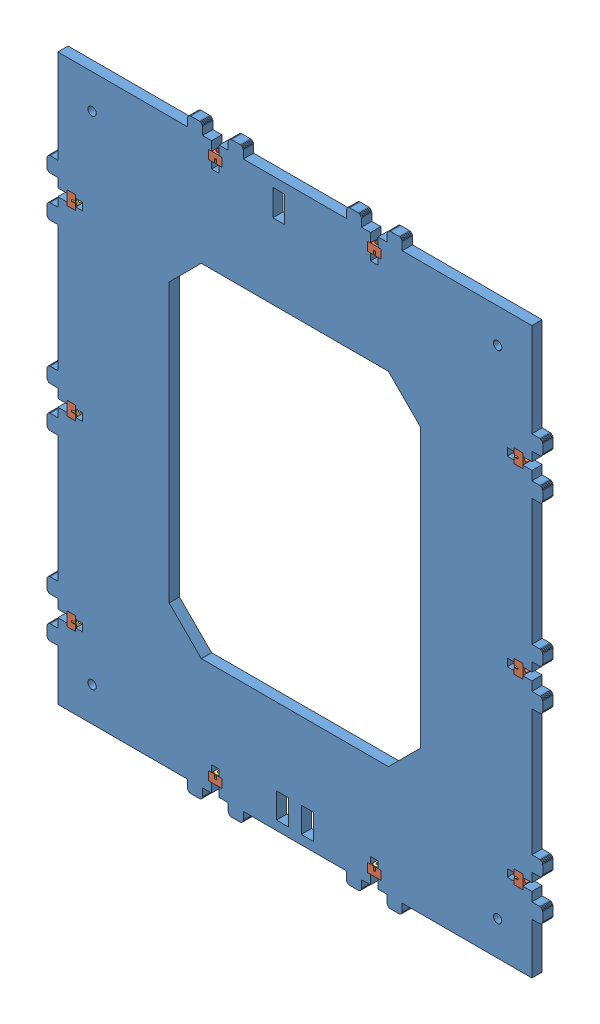
SolidWorks assembly Assembly Bottom, configuration Valor predeterminado. Lengths in mm.
Overall size (289.5 342.6 7.94).
31 component instances, 3 part files, 33 mates.
Components (placement in the parent):
- Bottom-1: Bottom [Valor predeterminado] at (-180.7925 178.2019 6) x (1 0 0) z (0 0 -1) size (289.5 342.6 6)
- Assembly m3-nut-adapter + Nut DIN 934 - M3-2: Assembly m3-nut-adapter + Nut DIN 934 - M3 [Valor predeterminado] at (-133.1 -118.95 3) x (0 -1 0) z (1 0 0) size (8.25 7.94 5.1)
  - m3-nut-adapter-1: m3-nut-adapter [Valor predeterminado] at origin size (8 6 5.1)
  - Nut DIN 934 - M3-1: Nut DIN 934 - M3 [Valor predeterminado] at (0 0 3.9) x (0 0 1) z (-0.866025 -0.5 0) size (2.4 5.5 6.35)
- Assembly m3-nut-adapter + Nut DIN 934 - M3-3: Assembly m3-nut-adapter + Nut DIN 934 - M3 [Valor predeterminado] at (-133.1 -12.5 3) x (0 -1 0) z (1 0 0) size (8.25 7.94 5.1)
  - m3-nut-adapter-1: m3-nut-adapter [Valor predeterminado] at origin size (8 6 5.1)
  - Nut DIN 934 - M3-1: Nut DIN 934 - M3 [Valor predeterminado] at (0 0 3.9) x (0 0 1) z (-0.866025 -0.5 0) size (2.4 5.5 6.35)
- Assembly m3-nut-adapter + Nut DIN 934 - M3-4: Assembly m3-nut-adapter + Nut DIN 934 - M3 [Valor predeterminado] at (-133.1 93.95 3) x (0 -1 0) z (1 0 0) size (8.25 7.94 5.1)
  - m3-nut-adapter-1: m3-nut-adapter [Valor predeterminado] at origin size (8 6 5.1)
  - Nut DIN 934 - M3-1: Nut DIN 934 - M3 [Valor predeterminado] at (0 0 3.9) x (0 0 1) z (-0.866025 -0.5 0) size (2.4 5.5 6.35)
- Assembly m3-nut-adapter + Nut DIN 934 - M3-5: Assembly m3-nut-adapter + Nut DIN 934 - M3 [Valor predeterminado] at (133.1 93.95 3) x (0 -1 0) z (-1 0 0) size (8.25 7.94 5.1)
  - m3-nut-adapter-1: m3-nut-adapter [Valor predeterminado] at origin size (8 6 5.1)
  - Nut DIN 934 - M3-1: Nut DIN 934 - M3 [Valor predeterminado] at (0 0 3.9) x (0 0 1) z (-0.866025 -0.5 0) size (2.4 5.5 6.35)
- Assembly m3-nut-adapter + Nut DIN 934 - M3-6: Assembly m3-nut-adapter + Nut DIN 934 - M3 [Valor predeterminado] at (133.1 -12.5 3) x (0 -1 0) z (-1 0 0) size (8.25 7.94 5.1)
  - m3-nut-adapter-1: m3-nut-adapter [Valor predeterminado] at origin size (8 6 5.1)
  - Nut DIN 934 - M3-1: Nut DIN 934 - M3 [Valor predeterminado] at (0 0 3.9) x (0 0 1) z (-0.866025 -0.5 0) size (2.4 5.5 6.35)
- Assembly m3-nut-adapter + Nut DIN 934 - M3-7: Assembly m3-nut-adapter + Nut DIN 934 - M3 [Valor predeterminado] at (133.1 -118.95 3) x (0 -1 0) z (-1 0 0) size (8.25 7.94 5.1)
  - m3-nut-adapter-1: m3-nut-adapter [Valor predeterminado] at origin size (8 6 5.1)
  - Nut DIN 934 - M3-1: Nut DIN 934 - M3 [Valor predeterminado] at (0 0 3.9) x (0 0 1) z (-0.866025 -0.5 0) size (2.4 5.5 6.35)
- Assembly m3-nut-adapter + Nut DIN 934 - M3-8: Assembly m3-nut-adapter + Nut DIN 934 - M3 [Valor predeterminado] at (-46.4 -159.6499 3) x (-1 0 0) z (0 1 0) size (8.25 7.94 5.1)
  - m3-nut-adapter-1: m3-nut-adapter [Valor predeterminado] at origin size (8 6 5.1)
  - Nut DIN 934 - M3-1: Nut DIN 934 - M3 [Valor predeterminado] at (0 0 3.9) x (0 0 1) z (-0.866025 -0.5 0) size (2.4 5.5 6.35)
- Assembly m3-nut-adapter + Nut DIN 934 - M3-9: Assembly m3-nut-adapter + Nut DIN 934 - M3 [Valor predeterminado] at (46.4 -159.6499 3) x (-1 0 0) z (0 1 0) size (8.25 7.94 5.1)
  - m3-nut-adapter-1: m3-nut-adapter [Valor predeterminado] at origin size (8 6 5.1)
  - Nut DIN 934 - M3-1: Nut DIN 934 - M3 [Valor predeterminado] at (0 0 3.9) x (0 0 1) z (-0.866025 -0.5 0) size (2.4 5.5 6.35)
- Assembly m3-nut-adapter + Nut DIN 934 - M3-10: Assembly m3-nut-adapter + Nut DIN 934 - M3 [Valor predeterminado] at (-46.4 159.6499 3) x (-1 0 0) z (0 -1 0) size (8.25 7.94 5.1)
  - m3-nut-adapter-1: m3-nut-adapter [Valor predeterminado] at origin size (8 6 5.1)
  - Nut DIN 934 - M3-1: Nut DIN 934 - M3 [Valor predeterminado] at (0 0 3.9) x (0 0 1) z (-0.866025 -0.5 0) size (2.4 5.5 6.35)
- Assembly m3-nut-adapter + Nut DIN 934 - M3-11: Assembly m3-nut-adapter + Nut DIN 934 - M3 [Valor predeterminado] at (46.4 159.6499 3) x (-1 0 0) z (0 -1 0) size (8.25 7.94 5.1)
  - m3-nut-adapter-1: m3-nut-adapter [Valor predeterminado] at origin size (8 6 5.1)
  - Nut DIN 934 - M3-1: Nut DIN 934 - M3 [Valor predeterminado] at (0 0 3.9) x (0 0 1) z (-0.866025 -0.5 0) size (2.4 5.5 6.35)
Mates (geometry in assembly coordinates):
- Coincidente2: coincident: plane of assembly through (0 0 0) normal (0 0 1); plane of Bottom-1 through (-180.7925 178.2019 0) normal (0 0 -1); plane of assembly
- Simétrico2: symmetric: plane of assembly; plane of assembly; plane of Bottom-1 through (138.4 -102.65 0) normal (1 0 0); plane of Bottom-1 through (-138.4 -28.8 0) normal (-1 0 0); plane of assembly
- Simétrico3: symmetric: plane of assembly; plane of assembly; plane of Bottom-1 through (62.7 -164.9499 0) normal (0 -1 0); plane of Bottom-1 through (-62.7 164.9499 0) normal (0 1 0); plane of assembly
- Coincidente3: coincident: plane of assembly; plane of assembly; plane of Bottom-1 through (-180.7925 178.2019 6) normal (0 0 1); plane of Assembly m3-nut-adapter + Nut DIN 934 - M3-2/m3-nut-adapter-1 through (-128 -114.95 6) normal (0 0 1)
- Coincidente4: coincident: plane of assembly; plane of assembly; plane of Bottom-1 through (-128 -122.95 0) normal (0 1 0); plane of Assembly m3-nut-adapter + Nut DIN 934 - M3-2/m3-nut-adapter-1 through (-128 -122.95 0) normal (0 -1 0)
- Coincidente5: coincident: plane of assembly; plane of assembly; plane of Bottom-1 through (-133.1 -122.95 0) normal (1 0 0); plane of Assembly m3-nut-adapter + Nut DIN 934 - M3-2/m3-nut-adapter-1 through (-133.1 -118.95 3) normal (-1 0 0)
- Coincidente6: coincident: plane of assembly; plane of assembly; plane of Bottom-1 through (-180.7925 178.2019 6) normal (0 0 1); plane of Assembly m3-nut-adapter + Nut DIN 934 - M3-3/m3-nut-adapter-1 through (-128 -8.5 6) normal (0 0 1)
- Coincidente7: coincident: plane of assembly; plane of assembly; plane of Bottom-1 through (-128 -16.5 0) normal (0 1 0); plane of Assembly m3-nut-adapter + Nut DIN 934 - M3-3/m3-nut-adapter-1 through (-128 -16.5 0) normal (0 -1 0)
- Coincidente8: coincident: plane of assembly; plane of assembly; plane of Bottom-1 through (-133.1 -16.5 0) normal (1 0 0); plane of Assembly m3-nut-adapter + Nut DIN 934 - M3-3/m3-nut-adapter-1 through (-133.1 -12.5 3) normal (-1 0 0)
- Coincidente9: coincident: plane of assembly; plane of assembly; plane of Bottom-1 through (-180.7925 178.2019 6) normal (0 0 1); plane of Assembly m3-nut-adapter + Nut DIN 934 - M3-4/m3-nut-adapter-1 through (-128 97.95 6) normal (0 0 1)
- Coincidente10: coincident: plane of assembly; plane of assembly; plane of Bottom-1 through (-133.1 97.95 0) normal (0 -1 0); plane of Assembly m3-nut-adapter + Nut DIN 934 - M3-4/m3-nut-adapter-1 through (-128 97.95 0) normal (0 1 0)
- Coincidente11: coincident: plane of assembly; plane of assembly; plane of Bottom-1 through (-133.1 89.95 0) normal (1 0 0); plane of Assembly m3-nut-adapter + Nut DIN 934 - M3-4/m3-nut-adapter-1 through (-133.1 93.95 3) normal (-1 0 0)
- Coincidente12: coincident: plane of assembly; plane of assembly; plane of Bottom-1 through (-180.7925 178.2019 6) normal (0 0 1); plane of Assembly m3-nut-adapter + Nut DIN 934 - M3-5/m3-nut-adapter-1 through (128 97.95 6) normal (0 0 1)
- Coincidente13: coincident: plane of assembly; plane of assembly; plane of Bottom-1 through (128 97.95 0) normal (0 -1 0); plane of Assembly m3-nut-adapter + Nut DIN 934 - M3-5/m3-nut-adapter-1 through (128 97.95 6) normal (0 1 0)
- Coincidente14: coincident: plane of assembly; plane of assembly; plane of Bottom-1 through (133.1 91.75 0) normal (-1 0 0); plane of Assembly m3-nut-adapter + Nut DIN 934 - M3-5/m3-nut-adapter-1 through (133.1 93.95 3) normal (1 0 0)
- Coincidente15: coincident: plane of assembly; plane of assembly; plane of Bottom-1 through (-180.7925 178.2019 6) normal (0 0 1); plane of Assembly m3-nut-adapter + Nut DIN 934 - M3-6/m3-nut-adapter-1 through (128 -8.5 6) normal (0 0 1)
- Coincidente16: coincident: plane of assembly; plane of assembly; plane of Bottom-1 through (133.1 -16.5 0) normal (0 1 0); plane of Assembly m3-nut-adapter + Nut DIN 934 - M3-6/m3-nut-adapter-1 through (128 -16.5 6) normal (0 -1 0)
- Coincidente17: coincident: plane of assembly; plane of assembly; plane of Bottom-1 through (133.1 -14.7 0) normal (-1 0 0); plane of Assembly m3-nut-adapter + Nut DIN 934 - M3-6/m3-nut-adapter-1 through (133.1 -12.5 3) normal (1 0 0)
- Coincidente18: coincident: plane of assembly; plane of assembly; plane of Bottom-1 through (-180.7925 178.2019 6) normal (0 0 1); plane of Assembly m3-nut-adapter + Nut DIN 934 - M3-7/m3-nut-adapter-1 through (128 -114.95 6) normal (0 0 1)
- Coincidente19: coincident: plane of assembly; plane of assembly; plane of Bottom-1 through (128 -114.95 0) normal (0 -1 0); plane of Assembly m3-nut-adapter + Nut DIN 934 - M3-7/m3-nut-adapter-1 through (128 -114.95 6) normal (0 1 0)
- Coincidente20: coincident: plane of assembly; plane of assembly; plane of Bottom-1 through (133.1 -114.95 0) normal (-1 0 0); plane of Assembly m3-nut-adapter + Nut DIN 934 - M3-7/m3-nut-adapter-1 through (133.1 -118.95 3) normal (1 0 0)
- Coincidente21: coincident: plane of assembly; plane of assembly; plane of Bottom-1 through (-180.7925 178.2019 6) normal (0 0 1); plane of Assembly m3-nut-adapter + Nut DIN 934 - M3-8/m3-nut-adapter-1 through (-42.4 -154.5499 6) normal (0 0 1)
- Coincidente22: coincident: plane of assembly; plane of assembly; plane of Bottom-1 through (-42.4 -154.55 0) normal (-1 0 0); plane of Assembly m3-nut-adapter + Nut DIN 934 - M3-8/m3-nut-adapter-1 through (-42.4 -154.5499 6) normal (1 0 0)
- Coincidente23: coincident: plane of assembly; plane of assembly; plane of Bottom-1 through (-48.6 -159.6499 0) normal (0 1 0); plane of Assembly m3-nut-adapter + Nut DIN 934 - M3-8/m3-nut-adapter-1 through (-46.4 -159.6499 3) normal (0 -1 0)
- Coincidente24: coincident: plane of assembly; plane of assembly; plane of Bottom-1 through (-180.7925 178.2019 6) normal (0 0 1); plane of Assembly m3-nut-adapter + Nut DIN 934 - M3-9/m3-nut-adapter-1 through (50.4 -154.5499 6) normal (0 0 1)
- Coincidente25: coincident: plane of assembly; plane of assembly; plane of Bottom-1 through (50.4 -154.55 0) normal (-1 0 0); plane of Assembly m3-nut-adapter + Nut DIN 934 - M3-9/m3-nut-adapter-1 through (50.4 -154.5499 6) normal (1 0 0)
- Coincidente26: coincident: plane of assembly; plane of assembly; plane of Bottom-1 through (50.4 -159.6499 0) normal (0 1 0); plane of Assembly m3-nut-adapter + Nut DIN 934 - M3-9/m3-nut-adapter-1 through (46.4 -159.6499 3) normal (0 -1 0)
- Coincidente27: coincident: plane of assembly; plane of assembly; plane of Bottom-1 through (-180.7925 178.2019 6) normal (0 0 1); plane of Assembly m3-nut-adapter + Nut DIN 934 - M3-10/m3-nut-adapter-1 through (-42.4 154.5499 6) normal (0 0 1)
- Coincidente28: coincident: plane of assembly; plane of assembly; plane of Bottom-1 through (-42.4 159.6499 0) normal (-1 0 0); plane of Assembly m3-nut-adapter + Nut DIN 934 - M3-10/m3-nut-adapter-1 through (-42.4 154.5499 0) normal (1 0 0)
- Coincidente29: coincident: plane of assembly; plane of assembly; plane of Bottom-1 through (-44.2 159.6499 0) normal (0 -1 0); plane of Assembly m3-nut-adapter + Nut DIN 934 - M3-10/m3-nut-adapter-1 through (-46.4 159.6499 3) normal (0 1 0)
- Coincidente30: coincident: plane of assembly; plane of assembly; plane of Bottom-1 through (-180.7925 178.2019 6) normal (0 0 1); plane of Assembly m3-nut-adapter + Nut DIN 934 - M3-11/m3-nut-adapter-1 through (50.4 154.5499 6) normal (0 0 1)
- Coincidente31: coincident: plane of assembly; plane of assembly; plane of Bottom-1 through (42.4 154.55 0) normal (1 0 0); plane of Assembly m3-nut-adapter + Nut DIN 934 - M3-11/m3-nut-adapter-1 through (42.4 154.5499 0) normal (-1 0 0)
- Coincidente32: coincident: plane of assembly; plane of assembly; plane of Bottom-1 through (48.6 159.6499 0) normal (0 -1 0); plane of Assembly m3-nut-adapter + Nut DIN 934 - M3-11/m3-nut-adapter-1 through (46.4 159.6499 3) normal (0 1 0)
